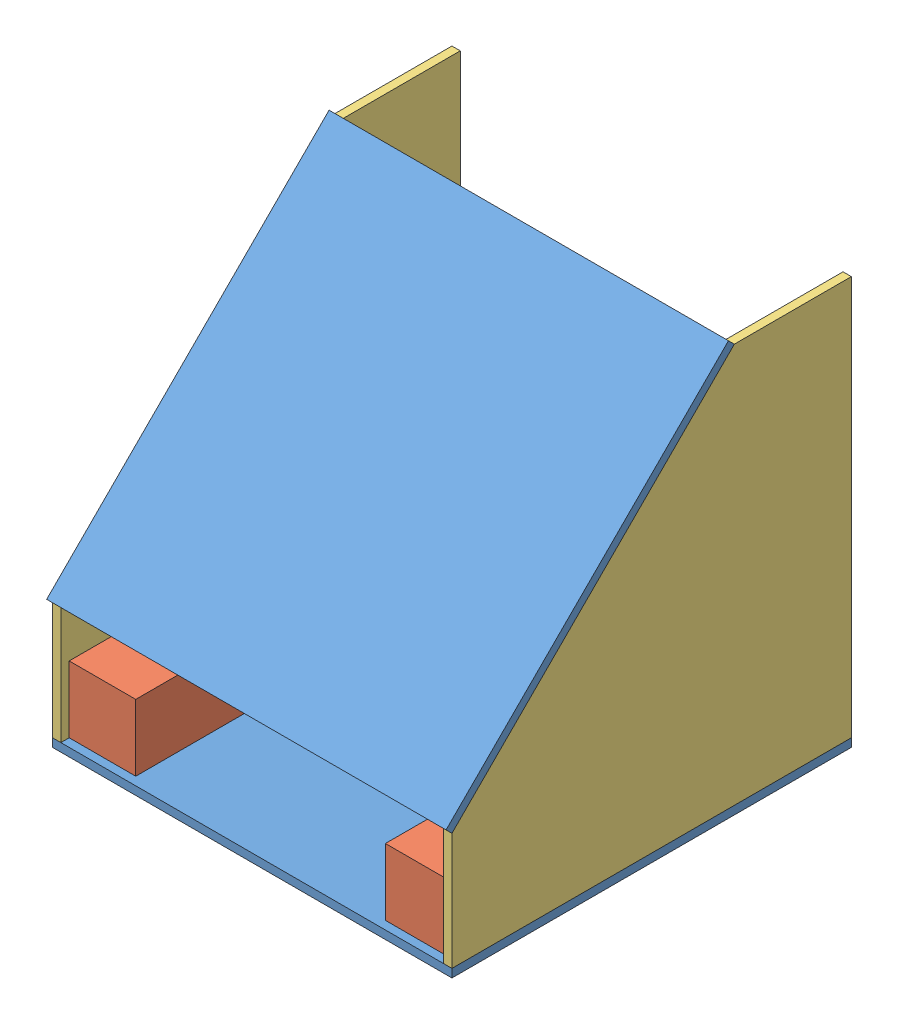
SolidWorks assembly Base Assembly, configuration Default. Lengths in mm.
Overall size (304.8 315.64 309.29).
6 component instances, 3 part files, 10 mates.
Components (placement in the parent):
- 12x12x0.25in Plywood Panel-2: 12x12x0.25in Plywood Panel [Default] at origin size (304.8 6.35 304.8)
- 2x2x11.5in Beam-1: 2x2x11.5in Beam [Default] at (-120.65 31.75 -146.05) size (50.8 50.8 292.1)
- 2x2x11.5in Beam-2: 2x2x11.5in Beam [Default] at (120.65 31.75 146.05) x (-1 0 0) z (0 0 -1) size (50.8 50.8 292.1)
- 0.25in Plywood Sidepanel-1: 0.25in Plywood Sidepanel [Default] at (146.05 158.75 0) size (6.35 304.8 304.8)
- 0.25in Plywood Sidepanel-2: 0.25in Plywood Sidepanel [Default] at (-152.4 158.75 0) size (6.35 304.8 304.8)
- 12x12x0.25in Plywood Panel-4: 12x12x0.25in Plywood Panel [Default] at (0 203.3869 44.6369) x (1 0 0) z (0 -0.707107 0.707107) size (304.8 6.35 304.8)
Mates (geometry in assembly coordinates):
- Coincident3: coordinate: point of 12x12x0.25in Plywood Panel-2; point of assembly
- Coincident4: coincident anti-aligned: plane of 12x12x0.25in Plywood Panel-2 through (0 6.35 0) normal (0 1 0); plane of 2x2x11.5in Beam-1 through (-146.05 6.35 146.05) normal (0 -1 0)
- Distance1: distance = 6.35 mm aligned: plane of 2x2x11.5in Beam-1 through (-146.05 6.35 146.05) normal (-1 0 0); plane of 12x12x0.25in Plywood Panel-2 through (-152.4 6.35 152.4) normal (-1 0 0)
- Distance2: distance = 6.35 mm aligned: plane of 2x2x11.5in Beam-1 through (-120.65 31.75 -146.05) normal (0 0 -1); plane of 12x12x0.25in Plywood Panel-2 through (-152.4 6.35 -152.4) normal (0 0 -1)
- Coincident11: coincident: point of 12x12x0.25in Plywood Panel-2; point of 0.25in Plywood Sidepanel-1
- Coincident12: coincident: point of 12x12x0.25in Plywood Panel-2; point of 0.25in Plywood Sidepanel-1
- Coincident13: coincident anti-aligned: plane of 12x12x0.25in Plywood Panel-2 through (0 6.35 0) normal (0 1 0); plane of 0.25in Plywood Sidepanel-1 through (152.4 6.35 152.4) normal (0 -1 0)
- Coincident14: coincident: point of 0.25in Plywood Sidepanel-2; point of 12x12x0.25in Plywood Panel-4
- Coincident15: coincident: point of 0.25in Plywood Sidepanel-1; point of 12x12x0.25in Plywood Panel-4
- Coincident16: coincident: line of 0.25in Plywood Sidepanel-2 through (-152.4 311.15 -63.1261) axis (0 -0.707107 0.707107); plane of 12x12x0.25in Plywood Panel-4 through (0 203.3869 44.6369) normal (0 -0.707107 -0.707107)
